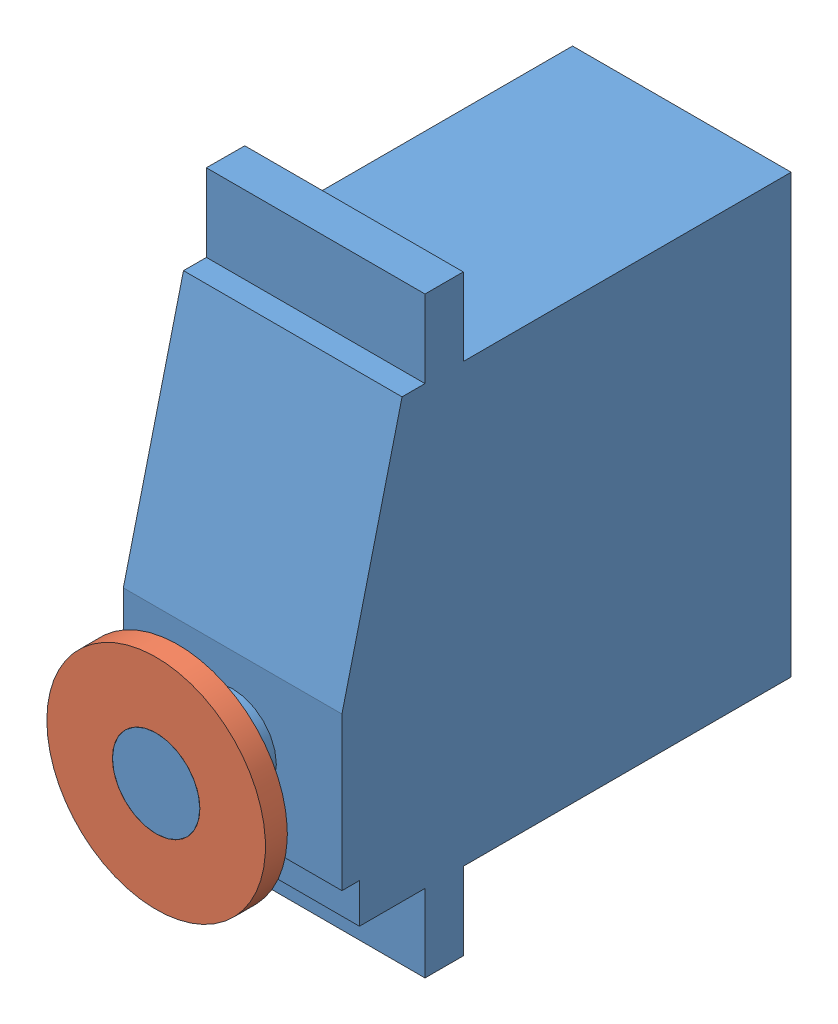
SolidWorks assembly Assem4, configuration Default. Lengths in mm.
Overall size (20.01 54.2 48.1).
2 component instances, 2 part files, 2 mates.
Components (placement in the parent):
- Servo-Body-6mm-1: Servo-Body-6mm [Default] at (8.2932 21.7501 21.9215) size (20.01 54.2 48.1)
- Servo-Horn-1: Servo-Horn [Default] at (8.2932 21.7501 68.0215) size (20 20 5.5)
Mates (geometry in assembly coordinates):
- Concentric2: concentric: cylinder of Servo-Body-6mm-1 through (8.2932 21.7501 70.0215) axis (0 0 -1) radius 4; cylinder of Servo-Horn-1 through (8.2932 21.7501 64.5215) axis (0 0 1) radius 4.5
- Coincident1: coincident aligned: plane of Servo-Body-6mm-1 through (8.2932 21.7501 70.0215) normal (0 0 1); plane of Servo-Horn-1 through (8.2932 21.7501 70.0215) normal (0 0 1)
